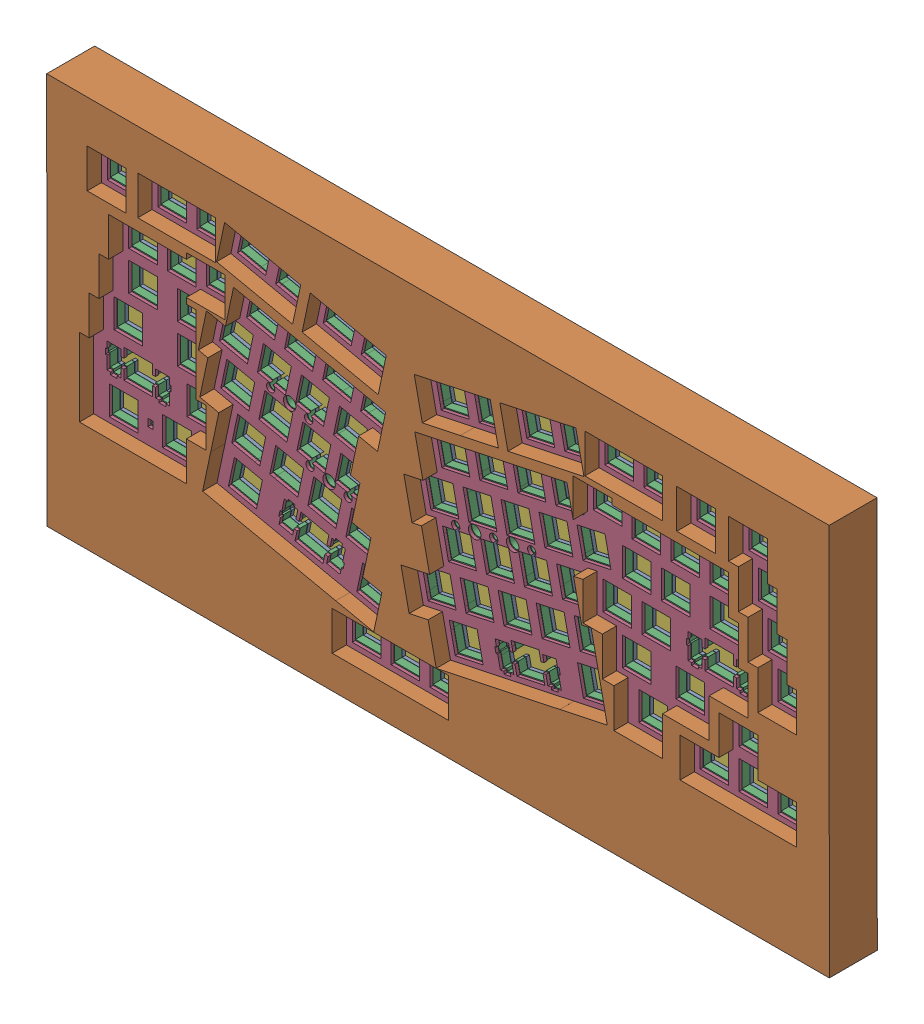
SolidWorks assembly 组装, configuration Default. Lengths in mm.
Overall size (383.5 192.04 277.26).
6 component instances, 6 part files, 5 mates.
Components (placement in the parent):
- PCB-1: PCB [Default] at (-96.4652 -48.9086 212.5308) size (351.47 160.02 1.6)
- 上壳-1: 上壳 [Default] at (-105.0415 -57.4882 202.8308) size (383.5 192.04 23.5)
- 夹心棉-1: 夹心棉 [Default] at (-96.6355 -49.032 214.1308) size (367.47 176.02 3.7)
- 定位板-1: 定位板 [Default] at (-96.7023 -49.5514 217.8308) size (367.47 176.02 1.5)
- 底壳-1: 底壳 [Default] at (-104.4311 -57.7634 202.8308) size (380.47 189.04 14.5)
- 底棉-1: 底棉 [Default] at (-100.4636 -54.476 211.2308) size (367.47 176.02 1.3)
Mates (geometry in assembly coordinates):
- 重合9: coincident anti-aligned: plane of 上壳-1 through (-105.0415 -57.4882 205.8308) normal (0 0 -1); plane of 底壳-1 through (-104.4311 -57.7634 205.8308) normal (0 0 1)
- 重合11: coincident anti-aligned: plane of 上壳-1 through (-105.0415 -57.4882 219.3308) normal (0 0 -1); plane of 定位板-1 through (-96.7023 -49.5514 219.3308) normal (0 0 1)
- 重合12: coincident anti-aligned: plane of 夹心棉-1 through (-96.6355 -49.032 217.8308) normal (0 0 1); plane of 定位板-1 through (-96.7023 -49.5514 217.8308) normal (0 0 -1)
- 重合13: coincident anti-aligned: plane of PCB-1 through (-96.4652 -48.9086 214.1308) normal (0 0 1); plane of 夹心棉-1 through (-96.6355 -49.032 214.1308) normal (0 0 -1)
- 重合14: coincident anti-aligned: plane of PCB-1 through (-96.4652 -48.9086 212.5308) normal (0 0 -1); plane of 底棉-1 through (-100.4636 -54.476 212.5308) normal (0 0 1)
